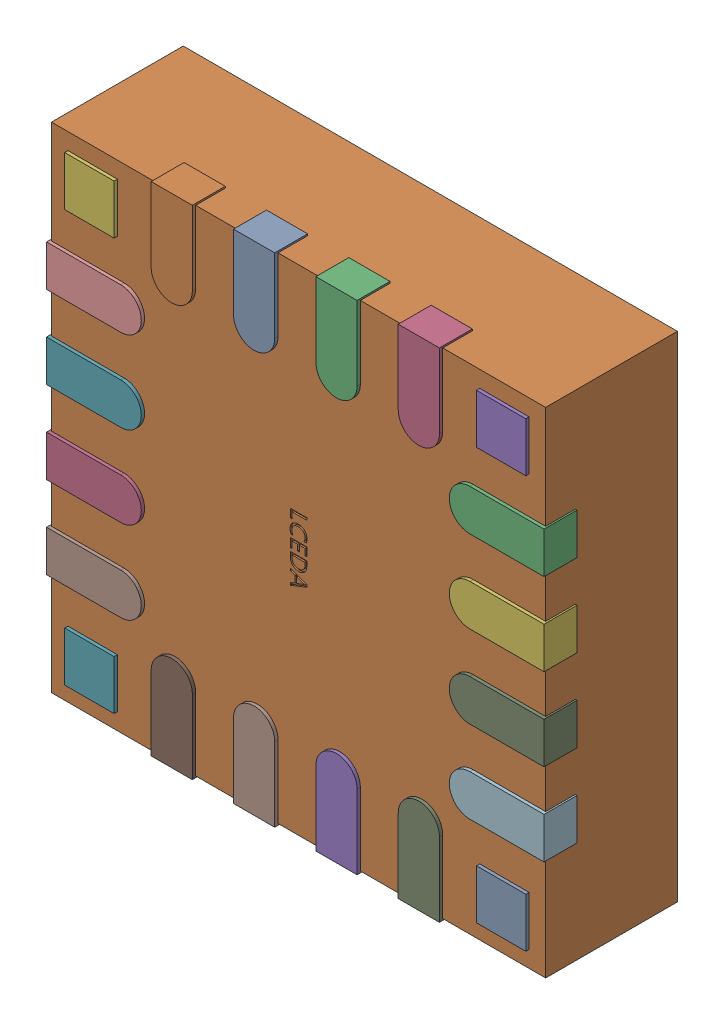
SolidWorks assembly U17, configuration Défaut. Lengths in mm.
Overall size (3.02 3.02 0.83).
4 component instances, 1 part files, 0 mates.
Components (placement in the parent):
- EFM8SB10F8G-A-QFN20-1: EFM8SB10F8G-A-QFN20 [Défaut] at (21.5321 3.9599 -0.4818) x (-1 0 0) z (0 0 -1) size (3.02 3.02 0.83)
  - U1.step_167-1: U1.step_167 [Défaut] at (5.0775 -6.7805 1.6001) size (3.02 3.02 0.83)
    - QFN-20_L3.0-W3.0-P0.50-BL-EP1.7_EFM8BB21F16G.step-1: QFN-20_L3.0-W3.0-P0.50-BL-EP1.7_EFM8BB21F16G.step [Défaut] at origin size (3.02 3.02 0.83)
      - COMPOUND.step_169-1: COMPOUND.step_169 [Défaut] at origin size (3.02 3.02 0.83)
